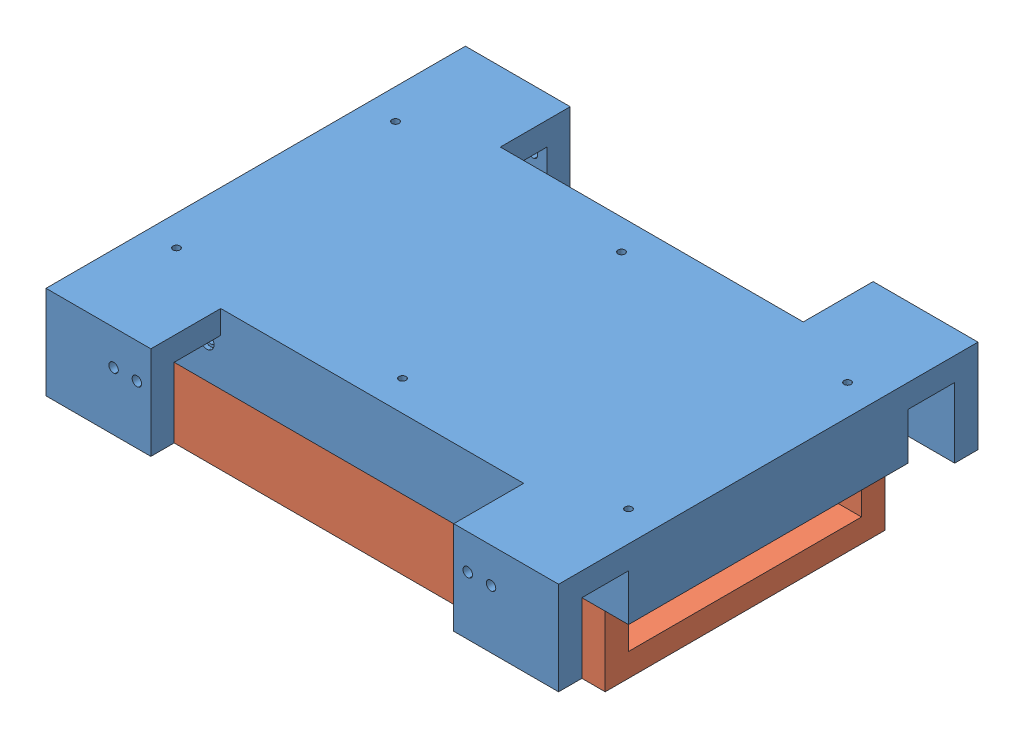
SolidWorks assembly DriveBattery, configuration Default. Lengths in mm.
Overall size (279.4 76.2 228.6).
2 component instances, 2 part files, 3 mates.
Components (placement in the parent):
- DriveBed-2: DriveBed [Default] at (33.291 125.4631 207.0748) size (279.4 57.15 228.6)
- BatteryCompartment-1: BatteryCompartment [Default] at (206.6433 119.1131 285.3779) x (0 0 -1) z (1 0 0) size (152.4 38.1 266.7)
Mates (geometry in assembly coordinates):
- Distance4: distance = 0 mm anti-aligned: plane of BatteryCompartment-1 through (206.6433 144.5131 285.3779) normal (0 1 0); plane of DriveBed-2 through (33.291 144.5131 207.0748) normal (0 -1 0)
- Distance5: distance = 0 mm aligned: plane of BatteryCompartment-1 through (206.6433 144.5131 298.0779) normal (0 0 1); plane of DriveBed-2 through (-47.3567 176.2631 298.0779) normal (0 0 1)
- Distance6: distance = 0 mm aligned: plane of BatteryCompartment-1 through (-60.0567 144.5131 285.3779) normal (-1 0 0); plane of DriveBed-2 through (-60.0567 176.2631 158.3779) normal (-1 0 0)
